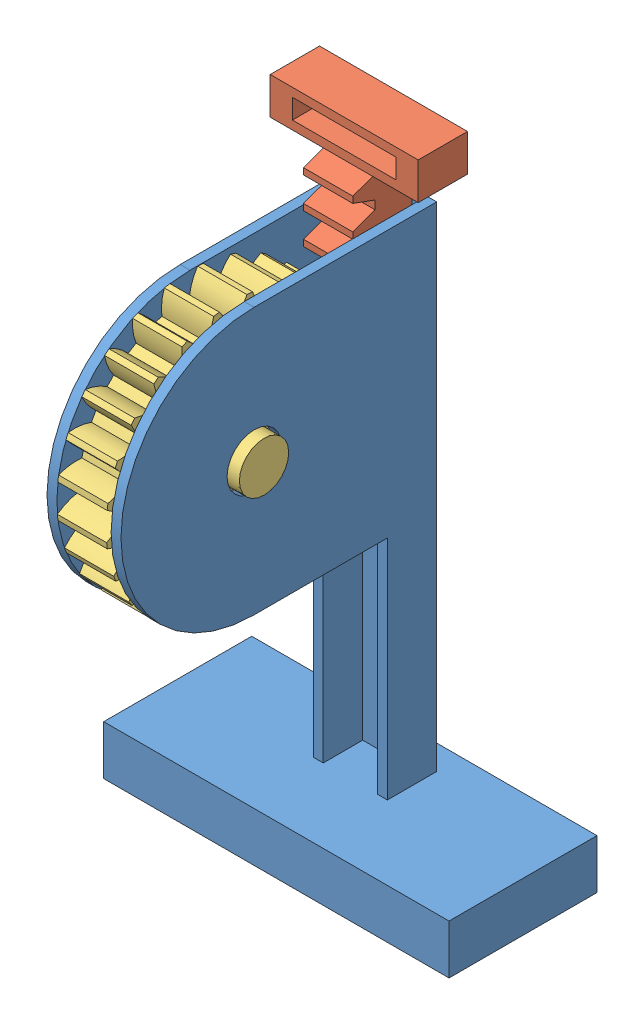
SolidWorks assembly ard_rpmstand, configuration Default. Lengths in mm.
Overall size (70 126.24 79.03).
3 component instances, 3 part files, 7 mates.
Components (placement in the parent):
- stand-1: stand [Default] at (-0.8299 8.8582 89.4482) size (70 110 69)
- rack-1: rack [Default] at (3.7179 139.9666 82.8284) x (0 1 0) z (1 0 0) size (57.5 13.25 30)
- spur-1: spur [Default] at (11.8542 82.4787 111.248) x (1 0 0) z (0 -0.522535 0.852618) size (20 53.85 53.95)
Mates (geometry in assembly coordinates):
- Parallel1: parallel: plane of stand-1 through (-6.3299 108.8582 81.4482) normal (0 0 1); plane of rack-1 through (-6.3299 67.5953 81.4482) normal (0 0 -1)
- Coincident3: coincident: plane of stand-1 through (-6.3299 108.8582 89.4482) normal (1 0 0); plane of rack-1 through (-6.3299 67.5953 93.4482) normal (-1 0 0)
- Coincident4: coincident: plane of stand-1 through (-6.3299 108.8582 81.4482) normal (0 0 1); plane of rack-1 through (-6.3299 67.5953 81.4482) normal (0 0 -1)
- Concentric1: concentric: cylinder of stand-1 through (-35.8299 81.8582 116.4482) axis (1 0 0) radius 5.5; cylinder of spur-1 through (8.6701 81.8582 116.4482) axis (-1 0 0) radius 5
- Concentric2: concentric: cylinder of stand-1 through (-35.8299 81.8582 116.4482) axis (1 0 0) radius 5.5; cylinder of spur-1 through (8.6701 81.8582 116.4482) axis (-1 0 0) radius 5
- Coincident5: coincident: plane of rack-1 through (3.6701 67.5953 93.4482) normal (1 0 0); plane of spur-1 through (3.6701 81.8582 116.4482) normal (1 0 0)
- RackPinionMate1: rack pinion = 54 mm: line of rack-1 through (3.6701 67.5953 81.4482) axis (0 1 0); circle of spur-1
